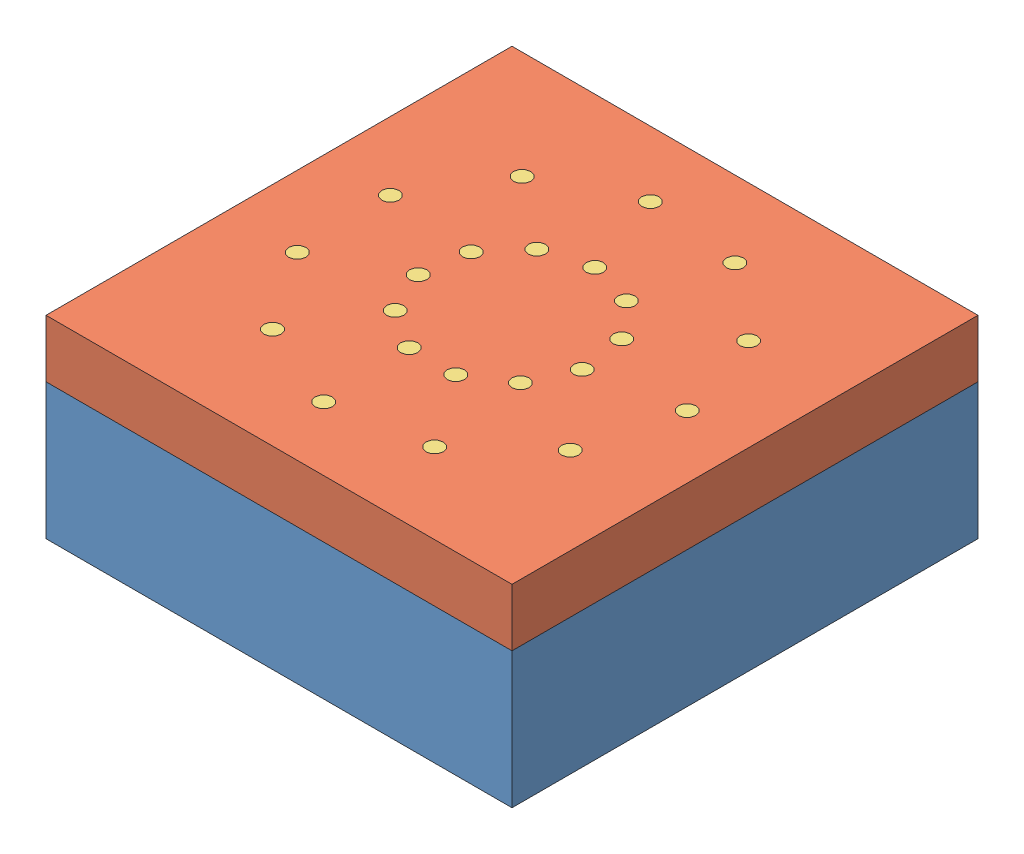
SolidWorks assembly Mold Assem, configuration Default. Lengths in mm.
Overall size (36 14.95 36).
3 component instances, 3 part files, 7 mates.
Components (placement in the parent):
- Cavity-1: Cavity [Default] at origin size (36 12.5 36)
- Cavity No Cavity-1: Cavity No Cavity [Default] at (0 13 0) x (-1 0 0) z (0 0 1) size (36 13.6 36)
- Mold Combine^Mold Assem-1: Mold Combine^Mold Assem [Default] at (0 10.95 0) x (1 0 0) z (0 1 0) size (35.16 35.16 13.6) (hidden, virtual)
Mates (geometry in assembly coordinates):
- Coincident5: coincident aligned: plane of Cavity-1 through (18 6.5 18) normal (1 0 0); plane of Cavity No Cavity-1 through (18 6.5 18) normal (1 0 0)
- Coincident6: coincident aligned: plane of Cavity-1 through (18 6.5 -18) normal (0 0 -1); plane of Cavity No Cavity-1 through (-18 6.5 -18) normal (0 0 -1)
- InPlace1: in place: plane of Cavity No Cavity-1 through (0 10.95 0) normal (0 1 0); plane of Mold Combine^Mold Assem-1 through (0 10.95 0) normal (0 1 0); moOrthogonalPlaneRef_w of Cavity No Cavity-1 through (0 10.95 0) normal (0 1 0); plane of Mold Combine^Mold Assem-1 through (0 10.95 0) normal (0 0 -1); plane of Cavity No Cavity-1 through (0 10.95 0) normal (0 1 0); plane of Mold Combine^Mold Assem-1 through (0 10.95 0) normal (1 0 0); plane of Cavity No Cavity-1 through (0 10.95 0) normal (0 1 0); unknown of Mold Combine^Mold Assem-1
- Coincident7: coincident aligned: plane of Cavity No Cavity-1; plane of Mold Combine^Mold Assem-1
- Coincident8: coincident aligned: moOrthogonalPlaneRef_w of Cavity No Cavity-1 through (0 10.95 0) normal (0 0 -1); plane of Mold Combine^Mold Assem-1 through (0 10.95 0) normal (0 0 -1)
- Coincident9: coincident anti-aligned: moOrthogonalPlaneRef_w of Cavity No Cavity-1 through (0 10.95 0) normal (-1 0 0); plane of Mold Combine^Mold Assem-1 through (0 10.95 0) normal (1 0 0)
- Coincident10: coincident anti-aligned: plane of Cavity-1 through (0 6.5 0) normal (0 1 0); plane of Cavity No Cavity-1 through (0 6.5 0) normal (0 -1 0)
